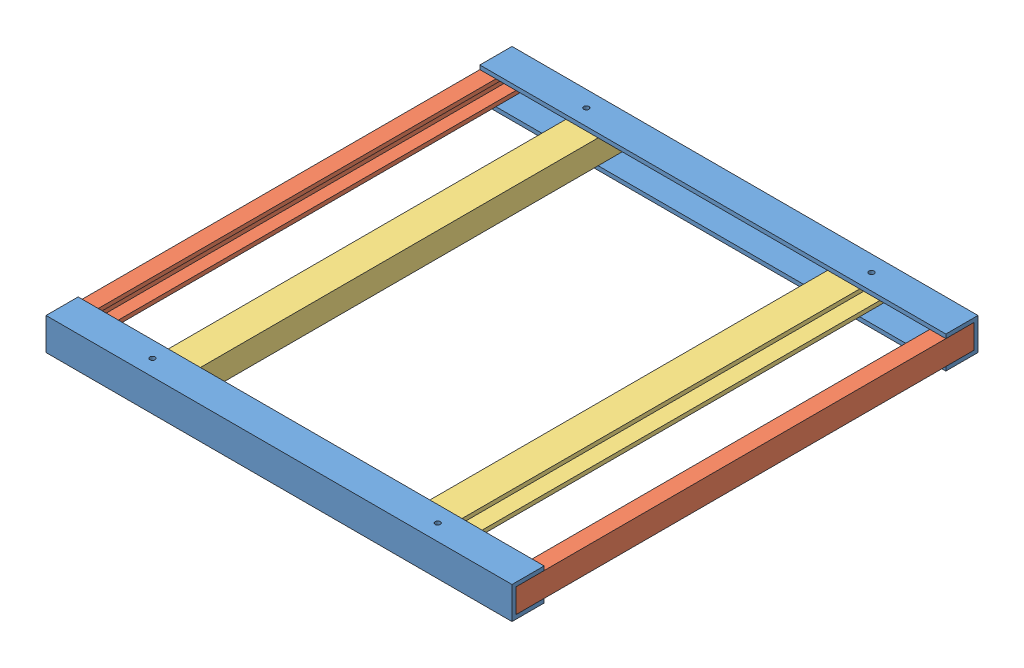
SolidWorks assembly CH_ASSEM_Base, configuration Default. Lengths in mm.
Overall size (368.3 25.4 368.3).
6 component instances, 3 part files, 9 mates.
Components (placement in the parent):
- CH_FrontBackChannel-2: CH_FrontBackChannel [Default] at (378.7562 204.4057 248.334) x (0 1 0) z (0 0 1) size (25.4 368.3 25.4)
- CH_SideOuterChannel-2: CH_SideOuterChannel [Default] at (23.1562 207.5807 226.109) x (0 1 0) z (1 0 0) size (19.05 361.95 12.7)
- CH_FrontBackChannel-3: CH_FrontBackChannel [Default] at (378.7562 229.8057 565.834) x (0 -1 0) z (0 0 -1) size (25.4 368.3 25.4)
- CH_SideInnerChannel-3: CH_SideInnerChannel [Default] at (78.5282 207.5807 588.059) x (0 1 0) z (-1 0 0) size (19.05 361.95 25.4)
- CH_SideInnerChannel-4: CH_SideInnerChannel [Default] at (310.6842 226.6307 588.059) x (0 -1 0) z (1 0 0) size (19.05 361.95 25.4)
- CH_SideOuterChannel-5: CH_SideOuterChannel [Default] at (366.0562 226.6307 226.109) x (0 -1 0) z (-1 0 0) size (19.05 361.95 12.7)
Mates (geometry in assembly coordinates):
- Coincident1: coincident anti-aligned: plane of CH_FrontBackChannel-2 through (10.4562 226.6307 226.109) normal (0 0 1); plane of CH_SideOuterChannel-2 through (23.1562 207.5807 226.109) normal (0 0 -1)
- Coincident2: coincident aligned: plane of CH_FrontBackChannel-2 through (10.4562 204.4057 248.334) normal (-1 0 0); plane of CH_SideOuterChannel-2 through (10.4562 207.5807 588.059) normal (-1 0 0)
- Coincident3: coincident anti-aligned: plane of CH_FrontBackChannel-2 through (10.4562 226.6307 248.334) normal (0 -1 0); plane of CH_SideOuterChannel-2 through (10.4562 226.6307 588.059) normal (0 1 0)
- Coincident4: coincident anti-aligned: plane of CH_SideOuterChannel-2 through (10.4562 226.6307 588.059) normal (0 1 0); plane of CH_FrontBackChannel-3 through (10.4562 226.6307 588.059) normal (0 -1 0)
- Coincident5: coincident anti-aligned: plane of CH_SideOuterChannel-2 through (23.1562 207.5807 588.059) normal (0 0 1); plane of CH_FrontBackChannel-3 through (10.4562 207.5807 588.059) normal (0 0 -1)
- Coincident6: coincident aligned: plane of CH_SideOuterChannel-2 through (10.4562 207.5807 588.059) normal (-1 0 0); plane of CH_FrontBackChannel-3 through (10.4562 229.8057 565.834) normal (-1 0 0)
- Coincident8: coincident anti-aligned: plane of CH_FrontBackChannel-2 through (10.4562 226.6307 226.109) normal (0 0 1); plane of CH_SideInnerChannel-3 through (78.5282 207.5807 226.109) normal (0 0 -1)
- Coincident10: coincident anti-aligned: plane of CH_FrontBackChannel-2 through (10.4562 207.5807 226.109) normal (0 1 0); plane of CH_SideInnerChannel-3 through (78.5282 207.5807 226.109) normal (0 -1 0)
- Distance1: distance = 55.372 mm anti-aligned: plane of CH_SideInnerChannel-3 through (78.5282 226.6307 226.109) normal (-1 0 0); plane of CH_SideOuterChannel-2 through (23.1562 226.6307 588.059) normal (1 0 0)
